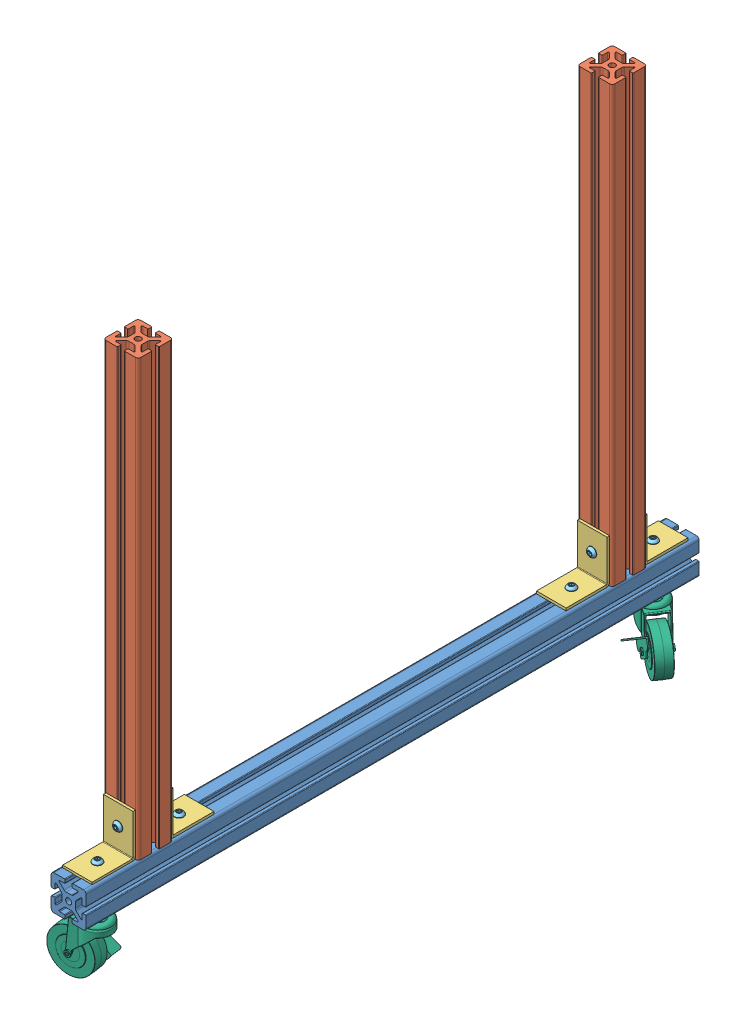
SolidWorks assembly Leg, configuration Default. Lengths in mm.
Overall size (96.25 615.51 705).
27 component instances, 6 part files, 78 mates.
Components (placement in the parent):
- 5537T712_T-Slotted Framing - Copy - Copy-2: 5537T712_T-Slotted Framing - Copy - Copy [5537T712] at (221.2591 328.215 425.3365) size (40 40 705)
- T-Slotted Framing - Leg Horizontal-1: T-Slotted Framing - Leg Horizontal [5537T712] at (221.2106 598.215 697.8365) x (0 0 -1) z (0 1 0) size (40 40 500)
- T-Slotted Framing - Leg Horizontal-2: T-Slotted Framing - Leg Horizontal [5537T712] at (221.2591 598.215 152.8365) x (0 0 -1) z (0 1 0) size (40 40 500)
- Connector-1: Connector [Default] at (238.2586 397.7192 717.8365) x (-1 0 0) z (0 0 1) size (34 50 50)
- T-Slot Nut-1: T-Slot Nut [90510A243] at (221.2586 337.7192 744.7048) size (13 10.81 13)
- T-Slot Nut-2: T-Slot Nut [90510A243] at (221.2586 374.5875 707.3407) x (1 0 0) z (0 -1 0) size (13 10.81 13)
- T-Slot Screw-1: T-Slot Screw [92095A224] at (221.2586 354.0192 744.7048) x (-0.969064 0 -0.246811) z (0 1 0) size (10.5 10.5 13.87)
- T-Slot Screw-2: T-Slot Screw [92095A224] at (221.2586 374.5875 724.1365) x (-0.673732 -0.738976 0) z (0 0 1) size (10.5 10.5 13.87)
- Connector-2: Connector [Default] at (204.3071 398.215 677.8365) x (1 0 0) z (0 0 -1) size (34 50 50)
- T-Slot Nut-3: T-Slot Nut [90510A243] at (221.3071 337.7192 650.9682) size (13 10.81 13)
- T-Slot Nut-4: T-Slot Nut [90510A243] at (221.3071 375.0833 688.3323) x (1 0 0) z (0 1 0) size (13 10.81 13)
- T-Slot Screw-3: T-Slot Screw [92095A224] at (221.3071 375.0833 671.5365) x (0.992761 -0.120103 0) z (0 0 -1) size (10.5 10.5 13.87)
- T-Slot Screw-4: T-Slot Screw [92095A224] at (221.3071 354.515 650.9682) x (0.549363 0 0.835584) z (0 1 0) size (10.5 10.5 13.87)
- Connector-3: Connector [Default] at (238.3071 348.215 82.8365) x (-1 0 0) z (0 1 0) size (34 50 50)
- T-Slot Nut-5: T-Slot Nut [90510A243] at (221.3071 337.7192 105.9682) size (13 10.81 13)
- T-Slot Screw-5: T-Slot Screw [92095A224] at (221.3071 354.515 105.9682) x (0.861668 0 0.507472) z (0 1 0) size (10.5 10.5 13.87)
- T-Slot Nut-6: T-Slot Nut [90510A243] at (221.3071 375.0833 143.3323) x (-1 0 0) z (0 -1 0) size (13 10.81 13)
- Connector-4: Connector [Default] at (238.2111 398.215 172.8365) x (-1 0 0) z (0 0 1) size (34 50 50)
- T-Slot Screw-6: T-Slot Screw [92095A224] at (221.3071 375.0833 126.5365) x (0.042978 -0.999076 0) z (0 0 -1) size (10.5 10.5 13.87)
- T-Slot Nut-7: T-Slot Nut [90510A243] at (221.2111 337.7192 199.7048) size (13 10.81 13)
- T-Slot Screw-7: T-Slot Screw [92095A224] at (221.2111 354.515 199.7048) x (-0.310093 0 -0.950706) z (0 1 0) size (10.5 10.5 13.87)
- T-Slot Nut-8: T-Slot Nut [90510A243] at (221.2111 375.0833 162.3407) x (-1 0 0) z (0 1 0) size (13 10.81 13)
- T-Slot Screw-8: T-Slot Screw [92095A224] at (221.2111 375.0833 179.1365) x (-0.835915 0.548859 0) z (0 0 1) size (10.5 10.5 13.87)
- 5537T314_T-Slotted Framing-1: 5537T314_T-Slotted Framing [5537T314] at (221.3071 300.4578 105.9682) x (-0.547749 0 0.836643) z (-0.836643 0 -0.547749) size (42.02 88.15 61.91)
- T-Slot Nut-9: T-Slot Nut [90510A243] at (221.3071 318.7108 105.9682) x (-1 0 0) z (0 0 1) size (13 10.81 13)
- 5537T314_T-Slotted Framing-2: 5537T314_T-Slotted Framing [5537T314] at (221.2586 300.4578 744.7048) x (-0.129653 0 -0.991559) z (0.991559 0 -0.129653) size (42.02 88.15 61.91)
- T-Slot Nut-10: T-Slot Nut [90510A243] at (221.2586 318.7108 744.7048) x (-1 0 0) z (0 0 1) size (13 10.81 13)
Mates (geometry in assembly coordinates):
- Parallel1: parallel aligned: plane of 5537T712_T-Slotted Framing - Copy - Copy-2 through (241.2591 345.167 777.8365) normal (1 0 0); plane of 5537T712_T-Slotted Framing - Copy-1 through (241.2106 848.215 680.8845) normal (1 0 0)
- Coincident3: coincident anti-aligned: plane of 5537T712_T-Slotted Framing - Copy-1 through (238.1626 848.215 717.8365) normal (0 0 1); plane of Connector-1 through (238.2586 347.7192 717.8365) normal (0 0 -1)
- Coincident4: coincident: line of 5537T712_T-Slotted Framing - Copy-1 through (204.2586 848.215 717.8365) axis (0 -1 0); plane of Connector-1 through (204.2586 347.7192 717.8365) normal (-1 0 0)
- Concentric1: concentric anti-aligned: circle of Connector-1; axis of 90510A243_Fully Threaded T-Slot Nut-1 through (221.2586 347.7192 744.7048) axis (0 -1 0)
- Coincident7: coincident anti-aligned: plane of 5537T712_T-Slotted Framing - Copy - Copy-2 through (217.2586 347.453 777.8365) normal (1 0 0); plane of 90510A243_Fully Threaded T-Slot Nut-1 through (217.2586 347.7192 751.2048) normal (-1 0 0)
- Coincident8: coincident anti-aligned: plane of 5537T712_T-Slotted Framing - Copy - Copy-2 through (216.4966 343.7192 777.8365) normal (0 -1 0); plane of 90510A243_Fully Threaded T-Slot Nut-1 through (214.7586 343.7192 751.2048) normal (0 1 0)
- Coincident9: coincident anti-aligned: plane of Connector-1 through (238.2586 347.7192 717.8365) normal (0 -1 0); plane of 90510A243_Fully Threaded T-Slot Nut-1 through (225.2586 347.7192 751.2048) normal (0 1 0)
- Concentric2: concentric anti-aligned: circle of Connector-1; line of 90510A243_Fully Threaded T-Slot Nut-2 through (221.2586 374.5875 717.3407) axis (0 0 -1)
- Parallel3: parallel anti-aligned: plane of 5537T712_T-Slotted Framing - Copy-1 through (217.2101 848.215 714.1027) normal (1 0 0); plane of 90510A243_Fully Threaded T-Slot Nut-2 through (217.2586 368.0875 717.3407) normal (-1 0 0)
- Coincident11: coincident anti-aligned: plane of 5537T712_T-Slotted Framing - Copy-1 through (210.9871 848.215 713.3407) normal (0 0 -1); plane of 90510A243_Fully Threaded T-Slot Nut-2 through (214.7586 368.0875 713.3407) normal (0 0 1)
- Coincident12: coincident anti-aligned: line of 90510A243_Fully Threaded T-Slot Nut-1 through (221.2586 347.7192 744.7048) axis (0 -1 0); line of 92095A224_Button Head Hex Drive Screw-1 through (221.2586 340.8197 744.7048) axis (0 1 0)
- Screw1: screw = 1 anti-aligned: cylinder of 90510A243_Fully Threaded T-Slot Nut-1 through (221.2586 347.7192 744.7048) axis (0 -1 0) radius 3; cylinder of 92095A224_Button Head Hex Drive Screw-1 through (221.2586 354.0192 744.7048) axis (0 1 0) radius 3
- Coincident13: coincident anti-aligned: plane of Connector-1 through (238.2586 350.7192 717.8365) normal (0 1 0); plane of 92095A224_Button Head Hex Drive Screw-1 through (216.171 350.7192 743.409) normal (0 -1 0)
- Distance2: distance = 60 mm aligned: plane of 5537T712_T-Slotted Framing - Copy-1 through (238.1626 848.215 717.8365) normal (0 0 1); plane of 5537T712_T-Slotted Framing - Copy - Copy-2 through (218.1845 338.9694 777.8365) normal (0 0 1)
- Coincident16: coincident aligned: line of Connector-1 through (221.2586 374.5875 717.8365) axis (0 0 1); line of 92095A224_Button Head Hex Drive Screw-2 through (221.2586 374.5875 710.9369) axis (0 0 1)
- Screw2: screw = 1 anti-aligned: cylinder of 90510A243_Fully Threaded T-Slot Nut-2 through (221.2586 374.5875 717.3407) axis (0 0 -1) radius 3; cylinder of 92095A224_Button Head Hex Drive Screw-2 through (221.2586 374.5875 724.1365) axis (0 0 1) radius 3
- Coincident17: coincident anti-aligned: plane of Connector-1 through (238.2586 347.7192 720.8365) normal (0 0 1); plane of 92095A224_Button Head Hex Drive Screw-2 through (217.7215 370.7079 720.8365) normal (0 0 -1)
- Coincident18: coincident aligned: line of 5537T712_T-Slotted Framing - Copy - Copy-2 through (204.3071 348.215 777.8365) axis (0 0 -1); line of Connector-2 through (204.3071 348.215 674.0999) axis (0 0 -1)
- Coincident20: coincident: plane of 5537T712_T-Slotted Framing - Copy-1 through (238.1626 848.215 677.8365) normal (0 0 -1); line of Connector-2 through (204.3071 351.9516 677.8365) axis (0 1 0)
- Coincident21: coincident anti-aligned: line of Connector-2 through (221.3071 375.0833 677.8365) axis (0 0 -1); line of 90510A243_Fully Threaded T-Slot Nut-4 through (221.3071 375.0833 678.3323) axis (0 0 1)
- Concentric3: concentric anti-aligned: circle of Connector-2; line of 90510A243_Fully Threaded T-Slot Nut-3 through (221.3071 347.7192 650.9682) axis (0 -1 0)
- Coincident22: coincident anti-aligned: plane of 5537T712_T-Slotted Framing - Copy - Copy-2 through (238.2111 348.215 777.8365) normal (0 1 0); plane of Connector-2 through (204.3071 348.215 677.8365) normal (0 -1 0)
- Parallel5: parallel anti-aligned: plane of 5537T712_T-Slotted Framing - Copy-1 through (225.2111 848.215 681.5703) normal (-1 0 0); plane of 90510A243_Fully Threaded T-Slot Nut-4 through (225.3071 381.5833 678.3323) normal (1 0 0)
- Coincident24: coincident anti-aligned: plane of 5537T712_T-Slotted Framing - Copy-1 through (231.4341 848.215 682.3323) normal (0 0 1); plane of 90510A243_Fully Threaded T-Slot Nut-4 through (225.3071 381.5833 682.3323) normal (0 0 -1)
- Coincident26: coincident anti-aligned: plane of 5537T712_T-Slotted Framing - Copy - Copy-2 through (204.3071 348.215 777.8365) normal (0 1 0); plane of 5537T712_T-Slotted Framing - Copy-1 through (210.4562 348.215 700.9111) normal (0 -1 0)
- Coincident27: coincident anti-aligned: line of 90510A243_Fully Threaded T-Slot Nut-4 through (221.3071 375.0833 678.3323) axis (0 0 1); line of 92095A224_Button Head Hex Drive Screw-3 through (221.3071 375.0833 675.9613) axis (0 0 -1)
- Screw3: screw = 1 anti-aligned: cylinder of 90510A243_Fully Threaded T-Slot Nut-4 through (221.3071 375.0833 678.3323) axis (0 0 1) radius 3; cylinder of 92095A224_Button Head Hex Drive Screw-3 through (221.3071 375.0833 671.5365) axis (0 0 -1) radius 3
- Coincident28: coincident anti-aligned: plane of Connector-2 through (204.3071 348.215 674.8365) normal (0 0 -1); plane of 92095A224_Button Head Hex Drive Screw-3 through (226.5191 374.4528 674.8365) normal (0 0 1)
- Parallel7: parallel anti-aligned: plane of 5537T712_T-Slotted Framing - Copy - Copy-2 through (217.2586 347.453 777.8365) normal (1 0 0); plane of 90510A243_Fully Threaded T-Slot Nut-3 through (217.3071 347.7192 657.4682) normal (-1 0 0)
- Coincident30: coincident anti-aligned: plane of 5537T712_T-Slotted Framing - Copy - Copy-2 through (226.0216 343.7192 777.8365) normal (0 -1 0); plane of 90510A243_Fully Threaded T-Slot Nut-3 through (225.3071 343.7192 657.4682) normal (0 1 0)
- Coincident31: coincident anti-aligned: line of 90510A243_Fully Threaded T-Slot Nut-3 through (221.3071 347.7192 650.9682) axis (0 -1 0); line of 92095A224_Button Head Hex Drive Screw-4 through (221.3071 350.0901 650.9682) axis (0 1 0)
- Screw4: screw = 1 anti-aligned: cylinder of 90510A243_Fully Threaded T-Slot Nut-3 through (221.3071 347.7192 650.9682) axis (0 -1 0) radius 3; cylinder of 92095A224_Button Head Hex Drive Screw-4 through (221.3071 354.515 650.9682) axis (0 1 0) radius 3
- Coincident32: coincident anti-aligned: plane of Connector-2 through (204.3071 351.215 677.8365) normal (0 1 0); plane of 92095A224_Button Head Hex Drive Screw-4 through (224.1913 351.215 655.355) normal (0 -1 0)
- Coincident35: coincident: line of 5537T712_T-Slotted Framing - Copy - Copy-2 through (238.2111 348.215 777.8365) axis (0 0 -1); point of 5537T712_T-Slotted Framing - Copy-2
- Coincident36: coincident: line of 5537T712_T-Slotted Framing - Copy - Copy-2 through (204.3071 348.215 777.8365) axis (0 0 -1); point of 5537T712_T-Slotted Framing - Copy-2
- Coincident37: coincident anti-aligned: plane of 5537T712_T-Slotted Framing - Copy - Copy-2 through (238.2111 348.215 777.8365) normal (0 1 0); plane of 5537T712_T-Slotted Framing - Copy-2 through (210.5047 348.215 155.9111) normal (0 -1 0)
- Distance4: distance = 60 mm aligned: plane of 5537T712_T-Slotted Framing - Copy-2 through (238.2111 848.215 132.8365) normal (0 0 -1); plane of 5537T712_T-Slotted Framing - Copy - Copy-2 through (218.1845 338.9694 72.8365) normal (0 0 -1)
- Coincident39: coincident aligned: line of 5537T712_T-Slotted Framing - Copy - Copy-2 through (204.3071 348.215 777.8365) axis (0 0 -1); line of Connector-3 through (204.3071 348.215 129.0999) axis (0 0 -1)
- Coincident40: coincident anti-aligned: plane of 5537T712_T-Slotted Framing - Copy-2 through (204.3071 848.215 132.8365) normal (0 0 -1); plane of Connector-3 through (238.3071 348.215 132.8365) normal (0 0 1)
- Concentric4: concentric anti-aligned: circle of Connector-3; line of 90510A243_Fully Threaded T-Slot Nut-5 through (221.3071 347.7192 105.9682) axis (0 -1 0)
- Parallel8: parallel anti-aligned: plane of 5537T712_T-Slotted Framing - Copy - Copy-2 through (217.2586 347.453 777.8365) normal (1 0 0); plane of 90510A243_Fully Threaded T-Slot Nut-5 through (217.3071 347.7192 112.4682) normal (-1 0 0)
- Coincident42: coincident anti-aligned: plane of 5537T712_T-Slotted Framing - Copy - Copy-2 through (216.4966 343.7192 777.8365) normal (0 -1 0); plane of 90510A243_Fully Threaded T-Slot Nut-5 through (214.8071 343.7192 112.4682) normal (0 1 0)
- Coincident43: coincident anti-aligned: line of 90510A243_Fully Threaded T-Slot Nut-5 through (221.3071 347.7192 105.9682) axis (0 -1 0); line of 92095A224_Button Head Hex Drive Screw-5 through (221.3071 341.3155 105.9682) axis (0 1 0)
- Screw5: screw = 1 anti-aligned: cylinder of 90510A243_Fully Threaded T-Slot Nut-5 through (221.3071 347.7192 105.9682) axis (0 -1 0) radius 3; cylinder of 92095A224_Button Head Hex Drive Screw-5 through (221.3071 354.515 105.9682) axis (0 1 0) radius 3
- Coincident44: coincident anti-aligned: plane of Connector-3 through (238.3071 351.215 132.8365) normal (0 1 0); plane of 92095A224_Button Head Hex Drive Screw-5 through (225.8309 351.215 108.6324) normal (0 -1 0)
- Concentric5: concentric anti-aligned: circle of Connector-3; line of 90510A243_Fully Threaded T-Slot Nut-6 through (221.3071 375.0833 133.3323) axis (0 0 1)
- Parallel9: parallel anti-aligned: plane of 5537T712_T-Slotted Framing - Copy-2 through (225.2596 848.215 136.5703) normal (-1 0 0); plane of 90510A243_Fully Threaded T-Slot Nut-6 through (225.3071 368.5833 133.3323) normal (1 0 0)
- Coincident47: coincident anti-aligned: plane of 5537T712_T-Slotted Framing - Copy-2 through (231.4826 848.215 137.3323) normal (0 0 1); plane of 90510A243_Fully Threaded T-Slot Nut-6 through (227.8071 368.5833 137.3323) normal (0 0 -1)
- Coincident48: coincident anti-aligned: line of 5537T712_T-Slotted Framing - Copy - Copy-2 through (238.2111 348.215 777.8365) axis (0 0 -1); line of Connector-4 through (238.2111 348.215 176.5731) axis (0 0 1)
- Coincident49: coincident anti-aligned: plane of 5537T712_T-Slotted Framing - Copy-2 through (238.2111 848.215 172.8365) normal (0 0 1); plane of Connector-4 through (238.2111 348.215 172.8365) normal (0 0 -1)
- Coincident50: coincident anti-aligned: plane of 5537T712_T-Slotted Framing - Copy - Copy-2 through (204.3071 348.215 777.8365) normal (0 1 0); plane of Connector-4 through (238.2111 348.215 172.8365) normal (0 -1 0)
- Coincident51: coincident anti-aligned: line of 90510A243_Fully Threaded T-Slot Nut-6 through (221.3071 375.0833 133.3323) axis (0 0 1); line of 92095A224_Button Head Hex Drive Screw-6 through (221.3071 375.0833 139.736) axis (0 0 -1)
- Screw6: screw = 1 anti-aligned: cylinder of 90510A243_Fully Threaded T-Slot Nut-6 through (221.3071 375.0833 133.3323) axis (0 0 1) radius 3; cylinder of 92095A224_Button Head Hex Drive Screw-6 through (221.3071 375.0833 126.5365) axis (0 0 -1) radius 3
- Coincident52: coincident anti-aligned: plane of Connector-3 through (238.3071 348.215 129.8365) normal (0 0 -1); plane of 92095A224_Button Head Hex Drive Screw-6 through (221.5328 369.8382 129.8365) normal (0 0 1)
- Concentric6: concentric anti-aligned: circle of Connector-4; line of 90510A243_Fully Threaded T-Slot Nut-7 through (221.2111 347.7192 199.7048) axis (0 -1 0)
- Parallel11: parallel anti-aligned: plane of 5537T712_T-Slotted Framing - Copy - Copy-2 through (217.2586 347.453 777.8365) normal (1 0 0); plane of 90510A243_Fully Threaded T-Slot Nut-7 through (217.2111 347.7192 206.2048) normal (-1 0 0)
- Coincident54: coincident anti-aligned: plane of 5537T712_T-Slotted Framing - Copy - Copy-2 through (226.0216 343.7192 777.8365) normal (0 -1 0); plane of 90510A243_Fully Threaded T-Slot Nut-7 through (225.2111 343.7192 206.2048) normal (0 1 0)
- Coincident55: coincident anti-aligned: line of 90510A243_Fully Threaded T-Slot Nut-7 through (221.2111 347.7192 199.7048) axis (0 -1 0); line of 92095A224_Button Head Hex Drive Screw-7 through (221.2111 350.0901 199.7048) axis (0 1 0)
- Screw7: screw = 1 anti-aligned: cylinder of 90510A243_Fully Threaded T-Slot Nut-7 through (221.2111 347.7192 199.7048) axis (0 -1 0) radius 3; cylinder of 92095A224_Button Head Hex Drive Screw-7 through (221.2111 354.515 199.7048) axis (0 1 0) radius 3
- Concentric7: concentric anti-aligned: circle of Connector-4; line of 90510A243_Fully Threaded T-Slot Nut-8 through (221.2111 375.0833 172.3407) axis (0 0 -1)
- Parallel13: parallel anti-aligned: plane of 5537T712_T-Slotted Framing - Copy-2 through (225.2596 848.215 169.1027) normal (-1 0 0); plane of 90510A243_Fully Threaded T-Slot Nut-8 through (225.2111 381.5833 172.3407) normal (1 0 0)
- Coincident59: coincident anti-aligned: plane of Connector-4 through (238.2111 351.215 172.8365) normal (0 1 0); plane of 92095A224_Button Head Hex Drive Screw-7 through (219.5831 351.215 194.7136) normal (0 -1 0)
- Coincident60: coincident anti-aligned: plane of 5537T712_T-Slotted Framing - Copy-2 through (231.4826 848.215 168.3407) normal (0 0 -1); plane of 90510A243_Fully Threaded T-Slot Nut-8 through (227.7111 381.5833 168.3407) normal (0 0 1)
- Coincident61: coincident anti-aligned: line of 90510A243_Fully Threaded T-Slot Nut-8 through (221.2111 375.0833 172.3407) axis (0 0 -1); line of 92095A224_Button Head Hex Drive Screw-8 through (221.2111 375.0833 165.9369) axis (0 0 1)
- Screw8: screw = 1 anti-aligned: cylinder of 90510A243_Fully Threaded T-Slot Nut-8 through (221.2111 375.0833 172.3407) axis (0 0 -1) radius 3; cylinder of 92095A224_Button Head Hex Drive Screw-8 through (221.2111 375.0833 179.1365) axis (0 0 1) radius 3
- Coincident62: coincident anti-aligned: plane of Connector-4 through (238.2111 348.215 175.8365) normal (0 0 1); plane of 92095A224_Button Head Hex Drive Screw-8 through (216.8226 377.9648 175.8365) normal (0 0 -1)
- Coincident63: coincident aligned: line of 92095A224_Button Head Hex Drive Screw-5 through (221.3071 341.3155 105.9682) axis (0 1 0); line of 90510A243_Fully Threaded T-Slot Nut-9 through (221.3071 308.7108 105.9682) axis (0 1 0)
- Parallel14: parallel anti-aligned: plane of 5537T712_T-Slotted Framing - Copy - Copy-2 through (217.2586 308.977 777.8365) normal (1 0 0); plane of 90510A243_Fully Threaded T-Slot Nut-9 through (217.3071 308.7108 112.4682) normal (-1 0 0)
- Coincident65: coincident anti-aligned: plane of 5537T712_T-Slotted Framing - Copy - Copy-2 through (216.4966 312.7108 777.8365) normal (0 1 0); plane of 90510A243_Fully Threaded T-Slot Nut-9 through (217.3071 312.7108 112.4682) normal (0 -1 0)
- Coincident66: coincident aligned: line of 5537T314_T-Slotted Framing-1 through (221.3071 300.4705 105.9682) axis (0 1 0); line of 90510A243_Fully Threaded T-Slot Nut-9 through (221.3071 308.7108 105.9682) axis (0 1 0)
- Screw9: screw = 1 aligned: cylinder of 5537T314_T-Slotted Framing-1 through (221.3071 293.9148 105.9682) axis (0 1 0) radius 3; cylinder of 90510A243_Fully Threaded T-Slot Nut-9 through (221.3071 308.7108 105.9682) axis (0 1 0) radius 3
- Coincident67: coincident anti-aligned: plane of 5537T712_T-Slotted Framing - Copy - Copy-2 through (218.1845 320.4578 777.8365) normal (0 -1 0); plane of 5537T314_T-Slotted Framing-1 through (221.3071 320.4578 105.9682) normal (0 1 0)
- Coincident68: coincident anti-aligned: line of 90510A243_Fully Threaded T-Slot Nut-1 through (221.2586 347.7192 744.7048) axis (0 -1 0); line of 90510A243_Fully Threaded T-Slot Nut-10 through (221.2586 308.7108 744.7048) axis (0 1 0)
- Coincident73: coincident anti-aligned: plane of 5537T712_T-Slotted Framing - Copy - Copy-2 through (217.2586 308.977 777.8365) normal (1 0 0); plane of 90510A243_Fully Threaded T-Slot Nut-10 through (217.2586 308.7108 751.2048) normal (-1 0 0)
- Coincident74: coincident anti-aligned: plane of 5537T712_T-Slotted Framing - Copy - Copy-2 through (216.4966 312.7108 777.8365) normal (0 1 0); plane of 90510A243_Fully Threaded T-Slot Nut-10 through (217.2586 312.7108 751.2048) normal (0 -1 0)
- Coincident75: coincident aligned: line of 5537T314_T-Slotted Framing-2 through (221.2586 300.4705 744.7048) axis (0 1 0); line of 90510A243_Fully Threaded T-Slot Nut-10 through (221.2586 308.7108 744.7048) axis (0 1 0)
- Screw10: screw = 1 aligned: cylinder of 5537T314_T-Slotted Framing-2 through (221.2586 293.9148 744.7048) axis (0 1 0) radius 3; cylinder of 90510A243_Fully Threaded T-Slot Nut-10 through (221.2586 308.7108 744.7048) axis (0 1 0) radius 3
- Coincident76: coincident anti-aligned: plane of 5537T712_T-Slotted Framing - Copy - Copy-2 through (218.1845 320.4578 777.8365) normal (0 -1 0); plane of 5537T314_T-Slotted Framing-2 through (221.2586 320.4578 744.7048) normal (0 1 0)
